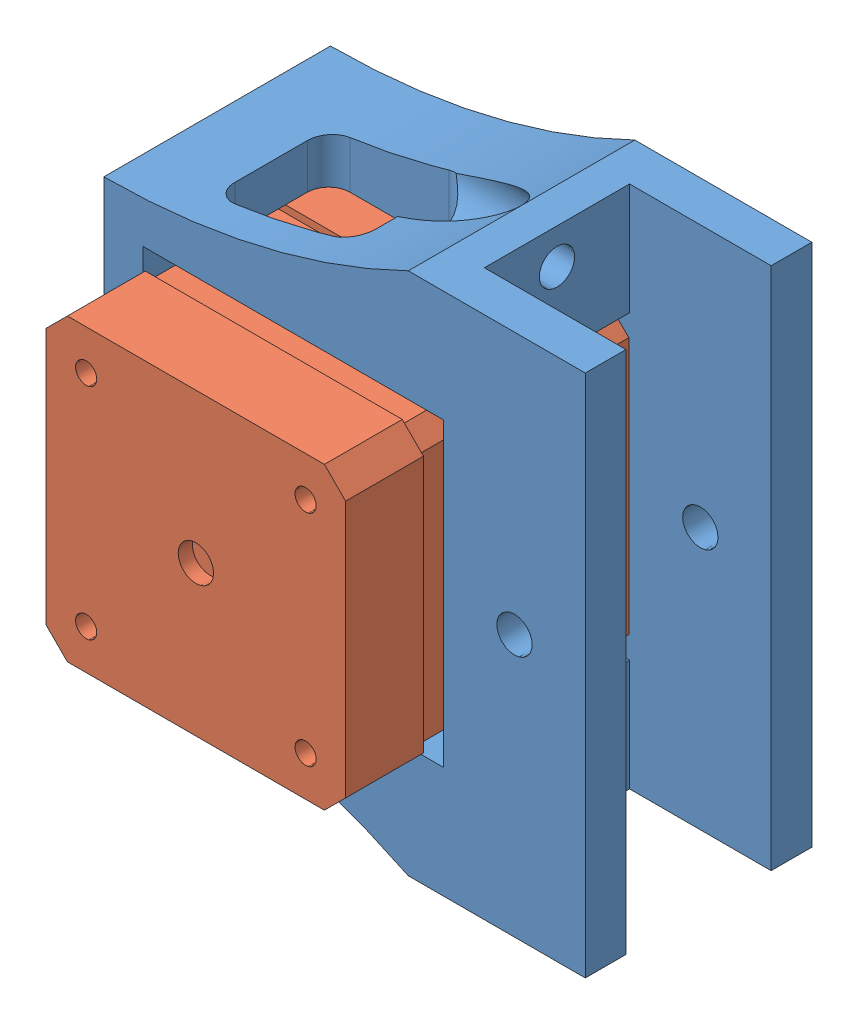
SolidWorks assembly Двигатель с креплением зеркально 2, configuration По умолчанию. Lengths in mm.
Overall size (68 74 63).
3 component instances, 3 part files, 9 mates.
Components (placement in the parent):
- Крепление двигателя зеркально-1: Крепление двигателя зеркально [По умолчанию] at (0 37 -26) size (68 74 32)
- Нема17-1: Нема17 [По умолчанию] at (-52.8678 35.3862 0.75) x (-1 0 0) z (0 0 -1) size (42.3 42.3 63)
- Шкив-1: Шкив [По умолчанию] at (-41.25 37 -15.85) x (-1 0 0) z (0 -1 0) size (18 17.4 18)
Mates (geometry in assembly coordinates):
- Совпадение1: coincident aligned: plane of Крепление двигателя зеркально-1 through (0 0 26) normal (1 0 0); plane of assembly through (0 0 0) normal (1 0 0)
- Совпадение2: coincident anti-aligned: plane of Крепление двигателя зеркально-1 through (0 0 26) normal (0 -1 0); plane of assembly through (0 0 0) normal (0 1 0)
- Совпадение3: coincident aligned: plane of Крепление двигателя зеркально-1 through (0 37 0) normal (0 0 1); plane of assembly through (0 0 0) normal (0 0 1)
- Концентричный1: concentric aligned: cylinder of Крепление двигателя зеркально-1 through (-56.75 52.5 -6.0074) axis (0 0 -1) radius 1.5; cylinder of Нема17-1 through (-56.75 52.5 37.25) axis (0 0 -1) radius 1.5
- Концентричный2: concentric aligned: cylinder of Крепление двигателя зеркально-1 through (-25.75 21.5 -6.0074) axis (0 0 -1) radius 1.5; cylinder of Нема17-1 through (-25.75 21.5 37.25) axis (0 0 -1) radius 1.5
- Совпадение4: coincident anti-aligned: plane of Крепление двигателя зеркально-1 through (-20 74 -10.25) normal (0 0 1); plane of Нема17-1 through (-52.8678 35.3862 -10.25) normal (0 0 -1)
- Концентричный3: concentric aligned: cylinder of Нема17-1 through (-41.25 37 -33.25) axis (0 0 1) radius 2.5; cylinder of Шкив-1 through (-41.25 37 -15.85) axis (0 0 1) radius 2.5
- Совпадение5: coincident aligned: plane of Нема17-1 through (-41.25 37 -33.25) normal (0 0 -1); plane of Шкив-1 through (-38.9558 37.9933 -33.25) normal (0 0 -1)
- Параллельность1: parallel anti-aligned: plane of Крепление двигателя зеркально-1 through (0 74 26) normal (0 1 0); plane of Шкив-1 through (-41.25 37 -15.85) normal (0 -1 0)
